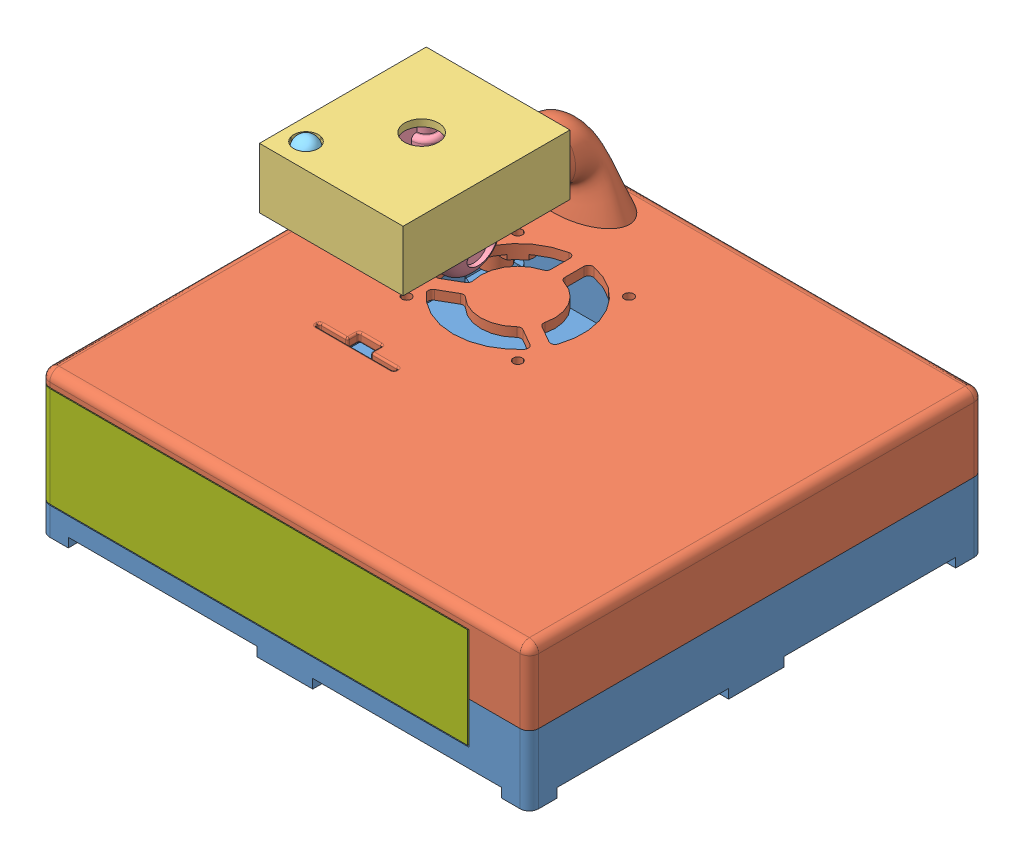
SolidWorks assembly Ensamblaje4, configuration Predeterminado. Lengths in mm.
Overall size (105.5 65.15 98).
8 component instances, 7 part files, 5 mates.
Components (placement in the parent):
- Base-1: Base [Predeterminado] at (-29.6553 -4.154 93.25) size (105.5 17 98)
- Tapa-1: Tapa [Predeterminado] at origin size (105.5 39.83 98)
- Cubre camara-1: Cubre camara [Predeterminado] at (-42.2202 89.596 103.1635) x (-1 0 0) z (0 -1 0) size (31 47.76 28.35)
  - Pieza2-1: Pieza2 [Predeterminado] at (-10.8149 0.4135 31.75) size (31 36 13)
  - Pieza3^Cubre camara-1: Pieza3^Cubre camara [Predeterminado] at origin size (27.94 32.94 21.4) (virtual)
  - 5mmLED-1: 5mmLED [默认] at (-0.0149 -13.7365 39.25) x (-0.097596 0.995226 0) z (0 0 -1) size (5.5 6 13.65)
  - Pieza8^Cubre camara-1: Pieza8^Cubre camara [Predeterminado] at origin size (13.16 29.04 12.21) (virtual)
- Tapa de Entradas-1: Tapa de Entradas [Predeterminado] at origin size (92.2 21.6 75.7)
Mates (geometry in assembly coordinates):
- Paralelo1: parallel aligned: plane of Pieza10^Ensamblaje4-1 through (0 0 0) normal (0 1 0); plane of Ensamblaje1-1/Pieza2-1 through (-31.4053 57.846 102.75) normal (0 1 0)
- Paralelo2: parallel aligned: plane of Pieza10^Ensamblaje4-1 through (-61.9053 22.846 58.5) normal (-1 0 0); plane of Ensamblaje1-1/Pieza2-1 through (-46.9053 49.346 113.25) normal (-1 0 0)
- Distancia1: distance = 15 mm aligned: plane of Pieza10^Ensamblaje4-1 through (-61.9053 22.846 58.5) normal (-1 0 0); plane of Ensamblaje1-1/Pieza2-1 through (-46.9053 49.346 113.25) normal (-1 0 0)
- Distancia3: distance = 20 mm anti-aligned: plane of Ensamblaje1-1/Pieza3^Ensamblaje1-1 through (-42.2202 44.846 103.1635) normal (0 -1 0); plane of Pieza10^Ensamblaje4-1 through (-59.9053 24.846 152.5) normal (0 1 0)
- Coincidente7: coincident anti-aligned: plane of Pieza10^Ensamblaje4-1 through (-35.4053 36.846 74.5) normal (0 0 1); plane of Ensamblaje1-1/Pieza8^Ensamblaje1-1 through (-35.4053 36.846 74.5) normal (0 0 -1)
